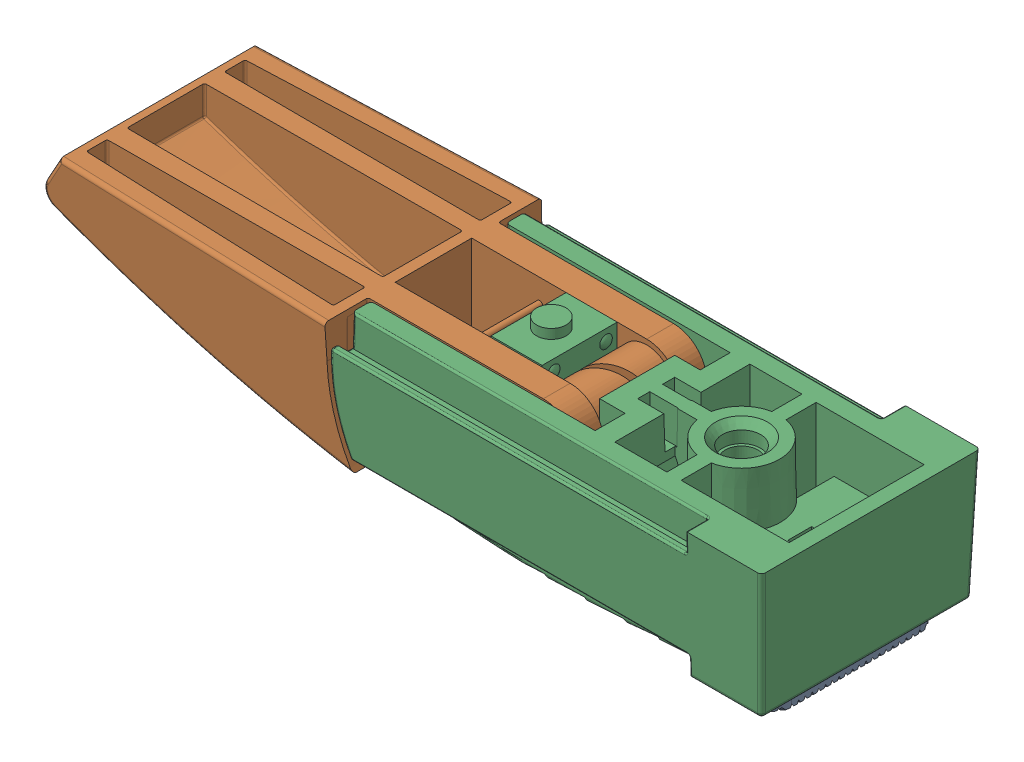
SolidWorks assembly 87646929_2, configuration По умолчанию. Lengths in mm.
Overall size (76.83 16.23 23.05).
3 component instances, 3 part files, 0 mates.
Components (placement in the parent):
- 60842027-1: 60842027 [По умолчанию] at (-13.1638 33.8211 0) x (-1 0 0) z (0 0 1) size (7.8 7.5 17.5)
- 87646931-1: 87646931 [По умолчанию] at (30.061 -56.7212 0) size (52.7 12.81 22.79)
- 87646929-1: 87646929 [По умолчанию] at (30.061 -56.7211 0) size (45.66 15.15 23.05)
